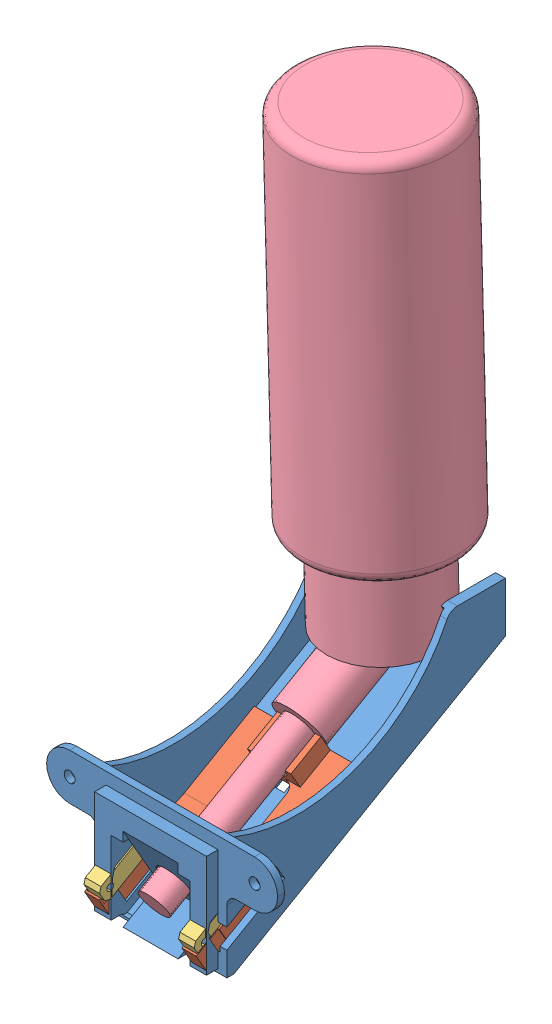
SolidWorks assembly bottleMountAssembly_222103, configuration Default. Lengths in mm.
Overall size (63.5 196.95 192.74).
5 component instances, 4 part files, 10 mates.
Components (placement in the parent):
- bottleMount_222103-1: bottleMount_222103 [Default] at (36.2876 4.8554 10.8624) size (63.5 56.87 79.72)
- bottlePivot_222103-1: bottlePivot_222103 [Static] at (36.2876 0.3251 -20.2221) x (-1 0 0) z (0 0.5 -0.866025) size (31.26 22.01 50.67)
- irOutline_sparkfun-1: irOutline_sparkfun [Default] at (25.4301 -12.4587 16.2138) x (0 -0.866025 -0.5) z (-1 0 0) size (5 12 4.3)
- irOutline_sparkfun-2: irOutline_sparkfun [Default] at (51.4451 -12.4587 16.2138) x (0 -0.866025 -0.5) z (-1 0 0) size (5 12 4.3)
- bottle-1: bottle [Default] at (36.2876 -11.723 14.9396) x (-0.99951 -0.027104 -0.015649) z (0 0.5 -0.866025) size (42 123.42 150.58)
Mates (geometry in assembly coordinates):
- Coincident1: coincident anti-aligned: plane of bottleMount_222103-1 through (21.1746 -12.0023 1.1296) normal (0 0.866025 0.5); plane of bottlePivot_222103-1 through (36.2876 5.0876 -28.471) normal (0 -0.866025 -0.5)
- Coincident2: coincident anti-aligned: plane of bottleMount_222103-1 through (38.5736 -47.1684 -19.1736) normal (-1 0 0); plane of bottlePivot_222103-1 through (38.5736 1.9126 -22.9717) normal (1 0 0)
- Coincident3: coincident anti-aligned: plane of bottlePivot_222103-1 through (36.2876 -5.8443 -0.2426) normal (0 0.866025 0.5); plane of irOutline_sparkfun-1 through (21.1301 -14.6238 14.9638) normal (0 -0.866025 -0.5)
- Coincident4: coincident anti-aligned: plane of bottlePivot_222103-1 through (21.1301 -9.8686 -2.5661) normal (1 0 0); plane of irOutline_sparkfun-1 through (21.1301 -12.4587 16.2138) normal (-1 0 0)
- Coincident5: coincident anti-aligned: plane of bottlePivot_222103-1 through (36.2876 -8.1417 7.7366) normal (0 -0.5 0.866025); plane of irOutline_sparkfun-1 through (21.1301 -7.7087 7.9866) normal (0 0.5 -0.866025)
- Coincident6: coincident anti-aligned: plane of bottlePivot_222103-1 through (36.2876 -5.8443 -0.2426) normal (0 0.866025 0.5); plane of irOutline_sparkfun-2 through (47.1451 -14.6238 14.9638) normal (0 -0.866025 -0.5)
- Coincident7: coincident anti-aligned: plane of bottlePivot_222103-1 through (51.4451 -9.8686 -2.5661) normal (-1 0 0); plane of irOutline_sparkfun-2 through (51.4451 -12.4587 16.2138) normal (1 0 0)
- Coincident8: coincident anti-aligned: plane of bottlePivot_222103-1 through (36.2876 -8.1417 7.7366) normal (0 -0.5 0.866025); plane of irOutline_sparkfun-2 through (47.1451 -7.7087 7.9866) normal (0 0.5 -0.866025)
- Concentric1: concentric aligned: cylinder of bottleMount_222103-1 through (36.2876 1.0308 -7.1507) axis (0 -0.5 0.866025) radius 4.3969; cylinder of bottle-1 through (36.2876 11.277 -24.8976) axis (0 -0.5 0.866025) radius 4
- Coincident9: coincident anti-aligned: plane of bottlePivot_222103-1 through (36.2876 5.0876 -28.471) normal (0 0.5 -0.866025); plane of bottle-1 through (36.2876 11.277 -24.8976) normal (0 -0.5 0.866025)
